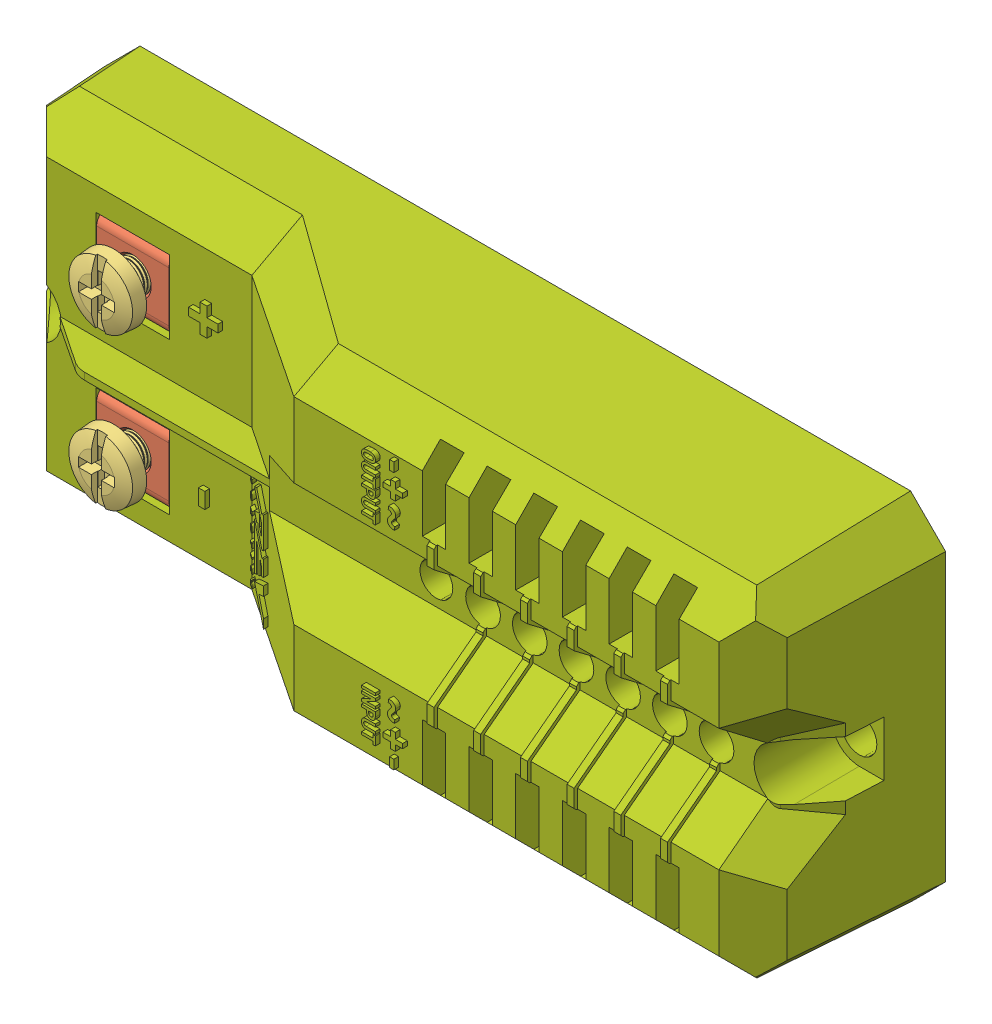
SolidWorks assembly PART_ASM_ServoPowerModule, configuration Default. Lengths in mm.
Overall size (91.44 38.73 20.66).
17 component instances, 8 part files, 0 mates.
Components (placement in the parent):
- PART_ServoPowerModule_RRSRVPUBD0HeightsPcb-1: PART_ServoPowerModule_RRSRVPUBD0HeightsPcb [Default] at origin size (78.74 35.56 1.6)
- PART_ServoPowerModule_ScrewTerminalAssembly-1: PART_ServoPowerModule_ScrewTerminalAssembly [Default] at (-0.5579 21.6861 -3.8497) x (0 1 0) z (1 0 0) size (7.87 11.69 7.87)
  - PART_ServoPowerModule_ScrewTerminalBase-1: PART_ServoPowerModule_ScrewTerminalBase [Default] at (3.4868 6.6312 8.3972) size (7.87 7.68 7.87)
  - PART_ServoPowerModule_ScrewTerminalScrew-1: PART_ServoPowerModule_ScrewTerminalScrew [Default] at (3.5041 -1.1314 8.5263) x (0.998152 0 -0.060771) z (0.060771 0 0.998152) size (7.16 8.3 7.16)
- PART_ServoPowerModule_ScrewTerminalAssembly-2: PART_ServoPowerModule_ScrewTerminalAssembly [Default] at (-0.5579 5.1761 -3.8497) x (0 1 0) z (1 0 0) size (7.87 11.69 7.87)
  - PART_ServoPowerModule_ScrewTerminalBase-1: PART_ServoPowerModule_ScrewTerminalBase [Default] at (3.4868 6.6312 8.3972) size (7.87 7.68 7.87)
  - PART_ServoPowerModule_ScrewTerminalScrew-1: PART_ServoPowerModule_ScrewTerminalScrew [Default] at (3.5041 -1.1314 8.5263) x (0.998152 0 -0.060771) z (0.060771 0 0.998152) size (7.16 8.3 7.16)
- PART_ServoPowerModule_Header-Female-1x3-PPTC031LFBN-RC-1: PART_ServoPowerModule_Header-Female-1x3-PPTC031LFBN-RC [Default] at (49.53 6.35 0.864) x (0 1 0) z (1 0 0) size (8.13 11.71 2.54)
- PART_ServoPowerModule_Header-Female-1x3-PPTC031LFBN-RC-2: PART_ServoPowerModule_Header-Female-1x3-PPTC031LFBN-RC [Default] at (54.61 6.35 0.864) x (0 1 0) z (1 0 0) size (8.13 11.71 2.54)
- PART_ServoPowerModule_Header-Female-1x3-PPTC031LFBN-RC-3: PART_ServoPowerModule_Header-Female-1x3-PPTC031LFBN-RC [Default] at (59.69 6.35 0.864) x (0 1 0) z (1 0 0) size (8.13 11.71 2.54)
- PART_ServoPowerModule_Header-Female-1x3-PPTC031LFBN-RC-4: PART_ServoPowerModule_Header-Female-1x3-PPTC031LFBN-RC [Default] at (64.77 6.35 0.864) x (0 1 0) z (1 0 0) size (8.13 11.71 2.54)
- PART_ServoPowerModule_Header-Female-1x3-PPTC031LFBN-RC-5: PART_ServoPowerModule_Header-Female-1x3-PPTC031LFBN-RC [Default] at (69.85 6.35 0.864) x (0 1 0) z (1 0 0) size (8.13 11.71 2.54)
- PART_ServoPowerModule_Header-Female-1x3-PPTC031LFBN-RC-6: PART_ServoPowerModule_Header-Female-1x3-PPTC031LFBN-RC [Default] at (74.93 6.35 0.864) x (0 1 0) z (1 0 0) size (8.13 11.71 2.54)
- PART_ServoPowerModule_Header-Male-11x3-EveryOtherNoPop-1: PART_ServoPowerModule_Header-Male-11x3-EveryOtherNoPop [Default] at (62.23 31.75 0.864) x (0 -1 0) z (-1 0 0) size (7.92 11.54 28.24)
- PART_ServoPowerModule_XLxx37-1: PART_ServoPowerModule_XLxx37 [Default] at (44.45 19.05 2.394) x (-0.707107 0.707107 0) z (0.707107 0.707107 0) size (3.2 8.3 3.2)
- PART_ServoPowerModule_TopShell-1: PART_ServoPowerModule_TopShell [Default] at (39.37 19.05 -0.736) x (0 1 0) z (1 0 0) size (38.73 20.66 91.44)
- PART_ServoPowerModule_Cover-1: PART_ServoPowerModule_Cover [Default] at (39.37 19.05 -2.3235) x (0 1 0) z (-1 0 0) size (35.94 2.35 88.65)
